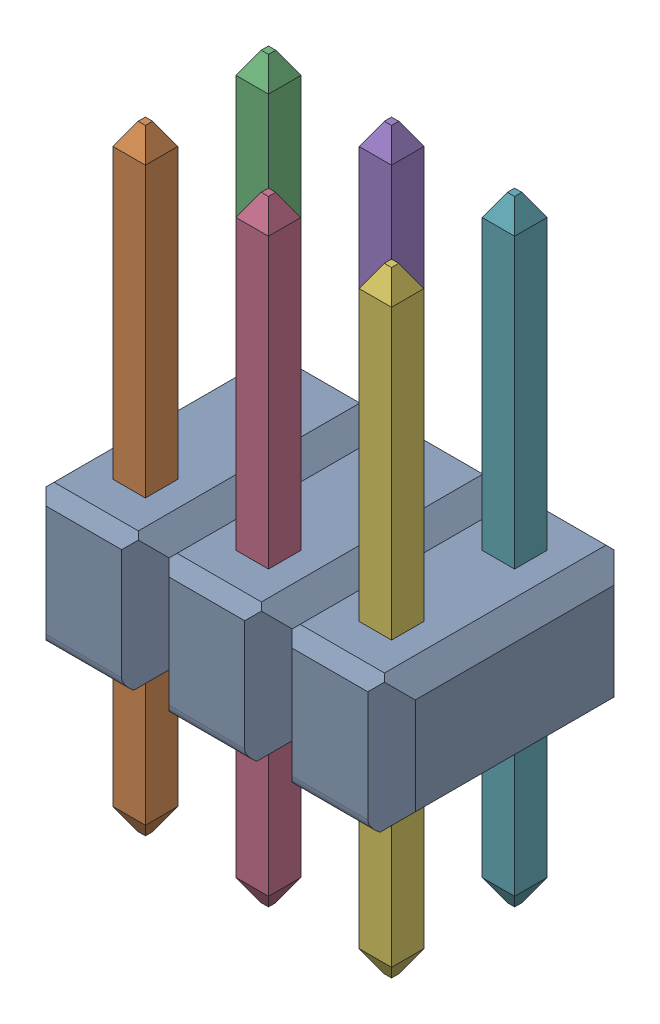
SolidWorks assembly User Library-2x3 TH Pitch 2_54mm, configuration ﾃﾞﾌｫﾙﾄ. Lengths in mm.
Overall size (7.62 12.7 5.08).
7 component instances, 2 part files, 0 mates.
Components (placement in the parent):
- header2x3-1: header2x3 [ﾃﾞﾌｫﾙﾄ] at (0 1.4 0) size (7.62 2.8 5.08)
- pin-1: pin [ﾃﾞﾌｫﾙﾄ] at (1.29 -3.5 1.29) size (0.67 12.7 0.67)
- pin-2: pin [ﾃﾞﾌｫﾙﾄ] at (1.29 -3.5 -1.25) size (0.67 12.7 0.67)
- pin-3: pin [ﾃﾞﾌｫﾙﾄ] at (3.83 -3.5 1.29) size (0.67 12.7 0.67)
- pin-4: pin [ﾃﾞﾌｫﾙﾄ] at (3.83 -3.5 -1.25) size (0.67 12.7 0.67)
- pin-5: pin [ﾃﾞﾌｫﾙﾄ] at (6.37 -3.5 1.29) size (0.67 12.7 0.67)
- pin-6: pin [ﾃﾞﾌｫﾙﾄ] at (6.37 -3.5 -1.25) size (0.67 12.7 0.67)
